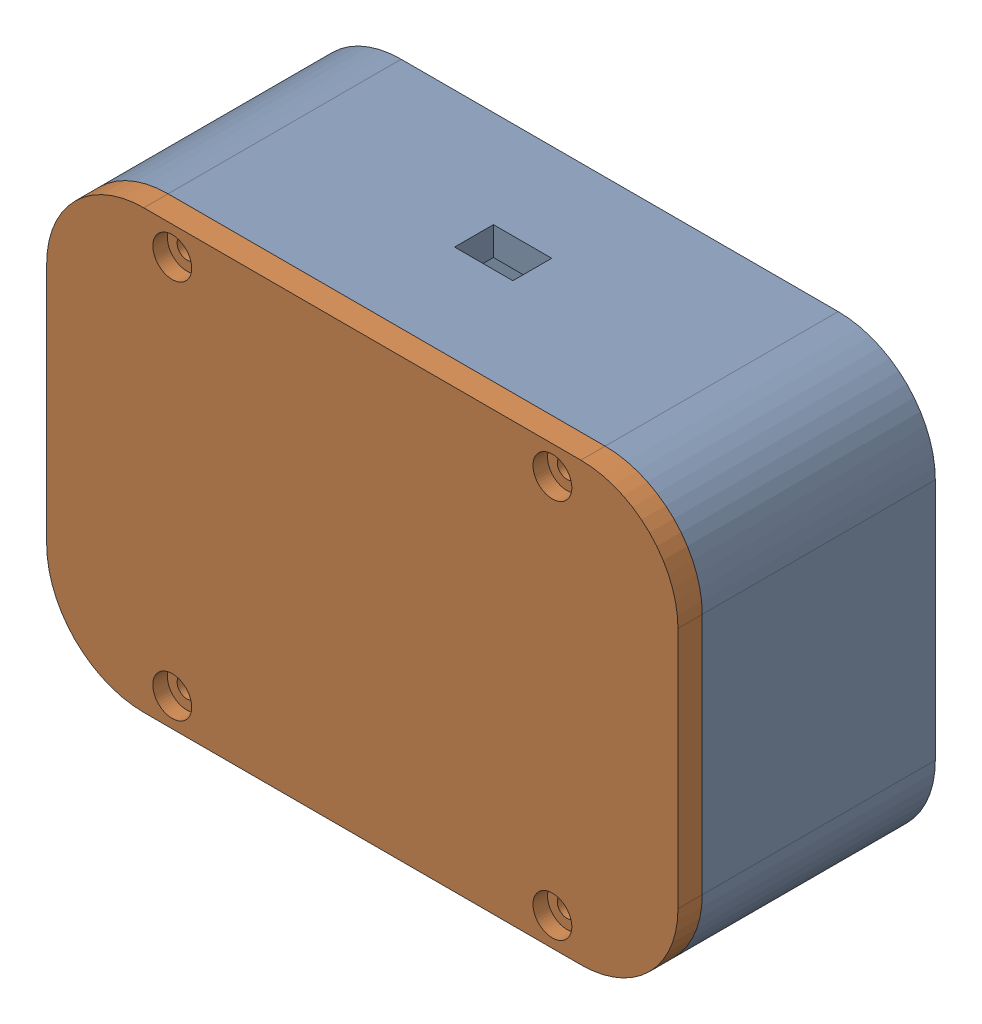
SolidWorks assembly Assem_controller, configuration Default. Lengths in mm.
Overall size (130 90 67.05).
4 component instances, 4 part files, 8 mates.
Components (placement in the parent):
- top-controller-1: top-controller [Default] at (-9.5226 29.2978 69.0336) size (130 90 48)
- bottom-controller-1: bottom-controller [Default] at (55.4774 74.2978 122.0336) x (1 0 0) z (0 0 -1) size (130 90 35)
- Joystick-HW504-Board-1: Joystick-HW504-Board [Varsayılan] at (17.3353 74.7978 87.0336) x (-1 0 0) z (0 -1 0) size (27.5 32.05 39.5)
- 12mm-Push-Button-1: 12mm-Push-Button [Default] at (89.3788 54.2978 75.1336) x (-1 0 0) z (0 -1 0) size (13.7 10.6 12)
Mates (geometry in assembly coordinates):
- Coincident5: coincident anti-aligned: plane of bottom controller-1 through (55.4774 74.2978 87.0336) normal (0 0 -1); plane of Joystick HW504 Board-1 through (17.3353 74.7978 87.0336) normal (0 0 1)
- Coincident6: coincident aligned: plane of bottom controller-1 through (3.8353 91.7978 87.0336) normal (0 1 0); plane of Joystick HW504 Board-1 through (30.8353 91.7978 86.0336) normal (0 1 0)
- Coincident7: coincident aligned: plane of bottom controller-1 through (3.8353 91.7978 87.0336) normal (-1 0 0); plane of Joystick HW504 Board-1 through (3.8353 91.7978 86.0336) normal (-1 0 0)
- Concentric2: concentric aligned: cylinder of top controller-1 through (16.3353 35.1557 94.0336) axis (0 0 1) radius 2; cylinder of bottom controller-1 through (16.3353 35.1557 117.0336) axis (0 0 1) radius 2
- Coincident8: coincident aligned: plane of top controller-1 through (-9.5226 29.2978 117.0336) normal (-1 0 0); plane of bottom controller-1 through (-9.5226 119.2978 117.0336) normal (-1 0 0)
- Coincident9: coincident anti-aligned: plane of top controller-1 through (-9.5226 29.2978 117.0336) normal (0 0 1); plane of bottom controller-1 through (55.4774 74.2978 117.0336) normal (0 0 -1)
- Coincident10: coincident: line of top-controller-1 through (84.3788 59.2978 72.0336) axis (0 -1 0); line of 12mm-Push-Button-1 through (84.3788 49.2978 72.0336) axis (0 1 0)
- Coincident11: coincident anti-aligned: line of top-controller-1 through (84.3788 49.2978 72.0336) axis (1 0 0); line of 12mm-Push-Button-1 through (94.3788 49.2978 72.0336) axis (-1 0 0)
